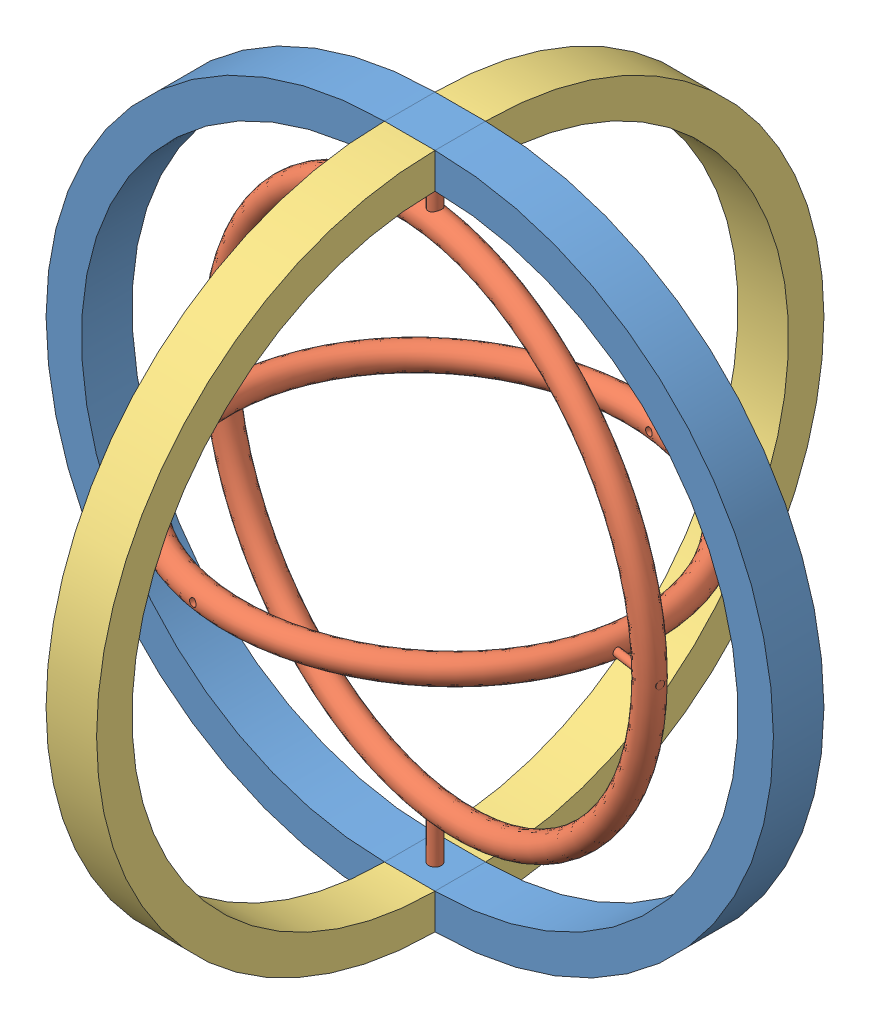
SolidWorks assembly Gimbal, configuration Default. Lengths in mm.
Overall size (144 134 144).
4 component instances, 3 part files, 7 mates.
Components (placement in the parent):
- Stand-1: Stand [Default] at origin size (144 134 10)
- Gimbal Ring-1: Gimbal Ring [Outer Ring] at (5 0 0) x (0 1 0) z (-0.140453 0 0.990087) size (125 105.08 5)
- Gimbal Ring-2: Gimbal Ring [Middle Ring] at (5 0 0) x (0.990087 0 0.140453) z (0.008154 0.998313 -0.057482) size (105 85.08 5)
- Stand2-1: Stand2 [Default] at (5 0 5) x (0 0 -1) z (1 0 0) size (144 134 10)
Mates (geometry in assembly coordinates):
- Coincident4: coincident anti-aligned: plane of Stand-1 through (5 -62.5 0) normal (0 1 0); plane of Gimbal Ring-1 through (5 -62.5 0) normal (0 -1 0)
- Coincident7: coincident aligned: axis of Gimbal Ring-1 through (-42.0729 0 -6.6777) axis (-0.990087 0 -0.140453); axis of Gimbal Ring-2 through (-37.015 0 -5.9602) axis (-0.990087 0 -0.140453)
- Coincident8: coincident: point of Gimbal Ring-1; point of Gimbal Ring-2
- Coincident11: coincident aligned: circle of Stand-1; circle of Gimbal Ring-1
- Coincident14: coincident anti-aligned: plane of Stand-1 through (0 -67 5) normal (0 0 1); plane of Stand2-1 through (10 60 5) normal (0 0 -1)
- Coincident15: coincident anti-aligned: line of Stand-1 through (10 67 5) axis (-1 0 0); line of Stand2-1 through (0 67 5) axis (1 0 0)
- Coincident16: coincident: point of Stand-1; point of Stand2-1
